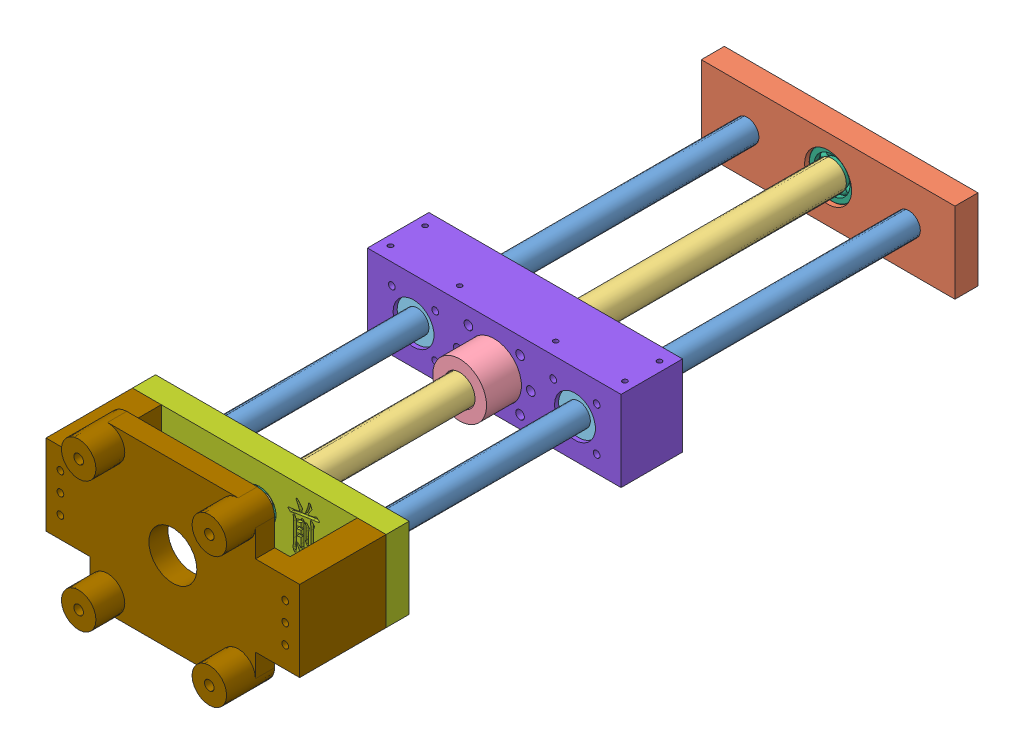
SolidWorks assembly 装配体1, configuration 默认. Lengths in mm.
Overall size (132 86 368).
12 component instances, 9 part files, 27 mates.
Components (placement in the parent):
- 光轴-1: 光轴 [默认] at (-69.0917 64.41 -160) size (12 12 290)
- 后-1: 后 [默认] at (-27.0917 64.41 -158) x (1 0 0) z (0 0 -1) size (132 42 12)
- 丝杠-1: 丝杠 [默认] at (-27.0917 64.41 -168) size (15 15 326.5)
- 丝母-1: 丝母 [默认] at (-27.0917 64.41 -16.2577) x (0 1 0) z (0 0 1) size (40 48 50)
- 轴套-1: 轴套 [默认] at (-69.0917 64.41 -16.2577) size (32 32 30)
- deep groove ball bearings gb-2: deep groove ball bearings gb [Rolling bearings 628 GB 276-94] at (-27.0917 64.41 131) x (0 0 -1) z (1 0 0) size (8 24 24)
- deep groove ball bearings gb-3: deep groove ball bearings gb [Rolling bearings 628 GB 276-94] at (-27.0917 64.41 -164) x (0 0 -1) z (1 0 0) size (8 24 24)
- 光轴-2: 光轴 [默认] at (14.9083 64.41 -160) size (12 12 290)
- 轴套-2: 轴套 [默认] at (14.9083 64.41 -16.2577) x (0 1 0) z (0 0 1) size (32 32 30)
- 前-2: 前 [默认] at (-27.0917 64.41 126) size (132 42 12)
- 中间-2: 中间 [默认] at (-27.0917 64.41 -16.2577) size (132 42 32)
- T-1: T [默认] at (-27.0917 64.41 173) size (132 86 60)
Mates (geometry in assembly coordinates):
- 同心6: concentric anti-aligned: cylinder of 光轴-1 through (-69.0917 64.41 -158) axis (0 0 -1) radius 4.5; cylinder of 后-1 through (-69.0917 64.41 -160) axis (0 0 1) radius 4.1
- 重合7: coincident anti-aligned: plane of 光轴-1 through (-69.0917 64.41 -160) normal (0 0 -1); plane of 后-1 through (-69.0917 64.41 -160) normal (0 0 1)
- 同心7: concentric anti-aligned: cylinder of 后-1 through (14.9083 64.41 -160) axis (0 0 1) radius 4.1; cylinder of 光轴-2 through (14.9083 64.41 -158) axis (0 0 -1) radius 4.5
- 同心8: concentric anti-aligned: cylinder of 丝杠-1 through (-27.0917 64.41 158.5) axis (0 0 -1) radius 4; cylinder of deep groove ball bearings gb-2 through (-27.0917 64.41 137.9714) axis (0 0 1) radius 4
- 重合8: coincident anti-aligned: plane of 丝杠-1 through (-27.0917 64.41 127) normal (0 0 1); plane of deep groove ball bearings gb-2 through (-27.0917 68.41 127) normal (0 0 -1)
- 同心9: concentric anti-aligned: cylinder of 丝杠-1 through (-27.0917 64.41 -160) axis (0 0 -1) radius 4; cylinder of deep groove ball bearings gb-3 through (-27.0917 64.41 -157.0286) axis (0 0 1) radius 4
- 重合9: coincident anti-aligned: plane of 丝杠-1 through (-27.0917 64.41 -160) normal (0 0 -1); plane of deep groove ball bearings gb-3 through (-27.0917 71.0766 -160) normal (0 0 1)
- 重合10: coincident anti-aligned: plane of 后-1 through (-27.0917 64.41 -168) normal (0 0 1); plane of deep groove ball bearings gb-3 through (-27.0917 76.41 -168) normal (0 0 -1)
- 同心10: concentric aligned: cylinder of 后-1 through (-27.0917 64.41 -168) axis (0 0 1) radius 12.25; cylinder of deep groove ball bearings gb-3 through (-27.0917 64.41 -155.2893) axis (0 0 1) radius 12
- 同心11: concentric anti-aligned: cylinder of 丝杠-1 through (-27.0917 64.41 127) axis (0 0 -1) radius 7.5; cylinder of 丝母-1 through (-27.0917 64.41 -16.2577) axis (0 0 1) radius 8
- 同心12: concentric anti-aligned: cylinder of 光轴-1 through (-69.0917 64.41 122) axis (0 0 -1) radius 6; cylinder of 轴套-1 through (-69.0917 64.41 -16.2577) axis (0 0 1) radius 6
- 同心13: concentric anti-aligned: cylinder of 光轴-2 through (14.9083 64.41 122) axis (0 0 -1) radius 6; cylinder of 轴套-2 through (14.9083 64.41 -16.2577) axis (0 0 1) radius 6
- 重合11: coincident aligned: plane of 丝母-1 through (-27.0917 64.41 -16.2577) normal (0 0 -1); plane of 轴套-2 through (14.9083 64.41 -16.2577) normal (0 0 -1)
- 重合12: coincident aligned: plane of 丝母-1 through (-27.0917 64.41 -16.2577) normal (0 0 -1); plane of 轴套-1 through (-69.0917 64.41 -16.2577) normal (0 0 -1)
- 重合13: coincident aligned: plane of 后-1 through (-93.0917 84.41 -170) normal (0 1 0); plane of 丝母-1 through (-40.3582 84.41 -6.2577) normal (0 1 0)
- 平行1: parallel aligned: plane of 后-1 through (-93.0917 84.41 -170) normal (0 1 0); plane of 轴套-2 through (1.3069 80.41 -10.2577) normal (0 1 0)
- 平行2: parallel aligned: plane of 后-1 through (-93.0917 84.41 -170) normal (0 1 0); plane of 轴套-1 through (-82.6931 80.41 -10.2577) normal (0 1 0)
- 同心14: concentric aligned: cylinder of 光轴-2 through (14.9083 64.41 130) axis (0 0 -1) radius 4.5; cylinder of 前-2 through (14.9083 64.41 130) axis (0 0 -1) radius 4.1
- 同心15: concentric aligned: cylinder of 光轴-1 through (-69.0917 64.41 130) axis (0 0 -1) radius 4.5; cylinder of 前-2 through (-69.0917 64.41 130) axis (0 0 -1) radius 4.1
- 同心16: concentric anti-aligned: cylinder of deep groove ball bearings gb-2 through (-27.0917 64.41 139.7107) axis (0 0 1) radius 12; cylinder of 前-2 through (-27.0917 64.41 136) axis (0 0 -1) radius 12.25
- 重合16: coincident anti-aligned: plane of 光轴-2 through (14.9083 64.41 130) normal (0 0 1); plane of 前-2 through (14.9083 64.41 130) normal (0 0 -1)
- 重合17: coincident anti-aligned: plane of 后-1 through (14.9083 64.41 -160) normal (0 0 1); plane of 光轴-2 through (14.9083 64.41 -160) normal (0 0 -1)
- 同心17: concentric aligned: cylinder of 丝母-1 through (-27.0917 64.41 -6.2577) axis (0 0 -1) radius 24; cylinder of 中间-2 through (-27.0917 64.41 -6.2577) axis (0 0 -1) radius 24.25
- 重合18: coincident aligned: plane of 丝母-1 through (-27.0917 64.41 -16.2577) normal (0 0 -1); plane of 中间-2 through (-27.0917 64.41 -16.2577) normal (0 0 -1)
- 重合19: coincident anti-aligned: plane of 前-2 through (-27.0917 64.41 138) normal (0 0 1); plane of T-1 through (-27.0917 64.41 138) normal (0 0 -1)
- 重合20: coincident aligned: plane of 前-2 through (-93.0917 84.41 138) normal (0 1 0); plane of T-1 through (38.9083 84.41 183) normal (0 1 0)
- 重合21: coincident aligned: plane of 前-2 through (38.9083 84.41 138) normal (1 0 0); plane of T-1 through (38.9083 84.41 183) normal (1 0 0)
